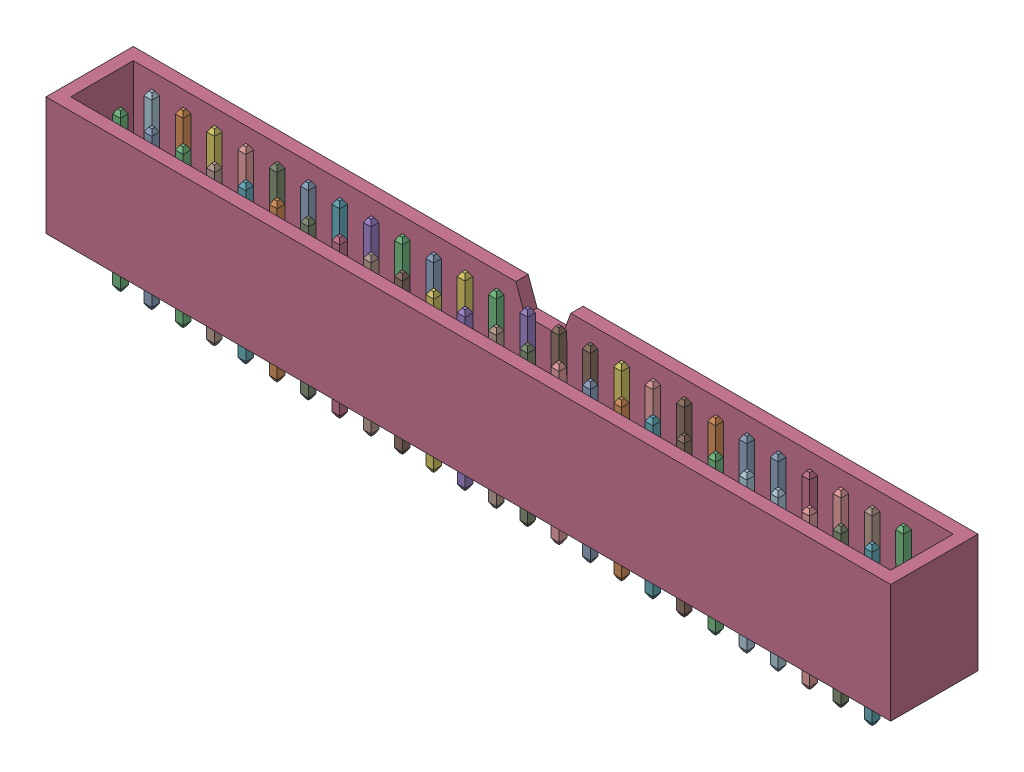
SolidWorks assembly 25 pin with case v2, configuration Default. Lengths in mm.
Overall size (68.5 12.8 7.08).
4 component instances, 3 part files, 0 mates.
Components (placement in the parent):
- Pin Header 2x15 TH Pitch 2-1: Pin Header 2x15 TH Pitch 2 [Default] at (0 0.0647 1.8778) x (1 0 0) z (0 1 0) size (38.1 5.08 12.7)
- Pin Header 2x10 TH Pitch 2-1: Pin Header 2x10 TH Pitch 2 [Default] at (38.1 0.0647 1.8778) x (1 0 0) z (0 1 0) size (25.4 5.08 12.7)
- 2X25Pin case v7-1: 2X25Pin case v7 [Default] x (1 0 0) z (0 1 0) size (68.5 7.08 9.6)
  - Component1 (6)-1: Component1 (6) [Default] at (-1.5 -1.8778 0.0661) size (68.5 7.08 9.6)
